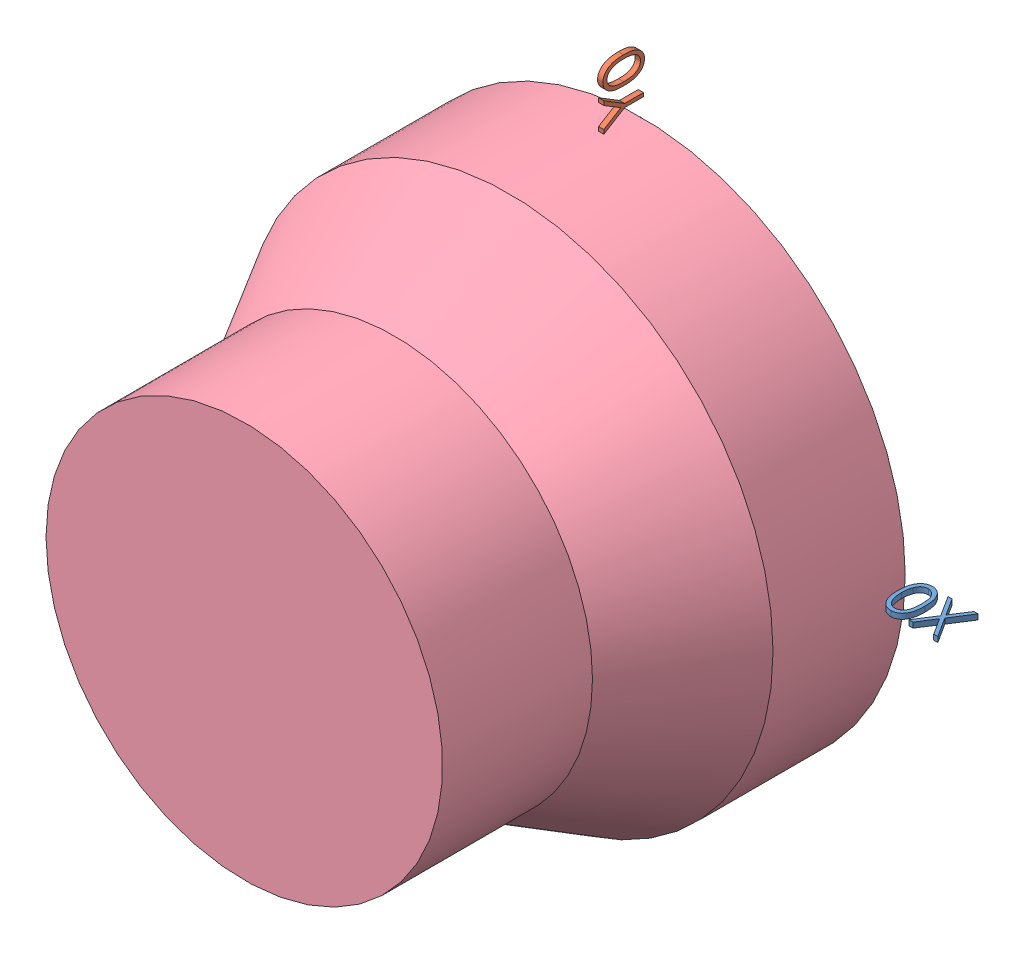
SolidWorks assembly link0, configuration Default. Lengths in mm.
Overall size (281.06 280.58 177.88).
5 component instances, 4 part files, 6 mates.
Components (placement in the parent):
- frame0_xyz-1: frame0_xyz [Default] at origin size (191.71 185.58 177.88)
  - frame_arrowX0-1: frame_arrowX0 [Default] x (0 0 -1) z (1 0 0) size (20.38 10 181.06)
  - frame_arrowY0-2: frame_arrowY0 [Default] x (0 0 1) z (0 1 0) size (20.38 10 180.58)
  - frame_arrowZ0-3: frame_arrowZ0 [Default] x (0 -1 0) z (0 0 1) size (10 20.19 172.88)
- link0-1: link0 [Default] at origin size (200 200 150)
Mates (geometry in assembly coordinates):
- Coincident4: coincident aligned: plane of frame0_xyz-1 through (0 0 0) normal (0 0 1); plane of link0-1 through (0 0 0) normal (0 0 1)
- Coincident5: coincident aligned: plane of frame0_xyz-1 through (0 0 0) normal (0 1 0); plane of link0-1 through (0 0 0) normal (0 1 0)
- Coincident6: coincident aligned: plane of frame0_xyz-1 through (0 0 0) normal (1 0 0); plane of link0-1 through (0 0 0) normal (1 0 0)
- Coincident7: coincident aligned: plane of frame0_xyz-1 through (0 0 0) normal (0 0 1)
- Coincident8: coincident aligned: plane of frame0_xyz-1 through (0 0 0) normal (0 1 0)
- Coincident9: coincident aligned: plane of frame0_xyz-1 through (0 0 0) normal (1 0 0)
